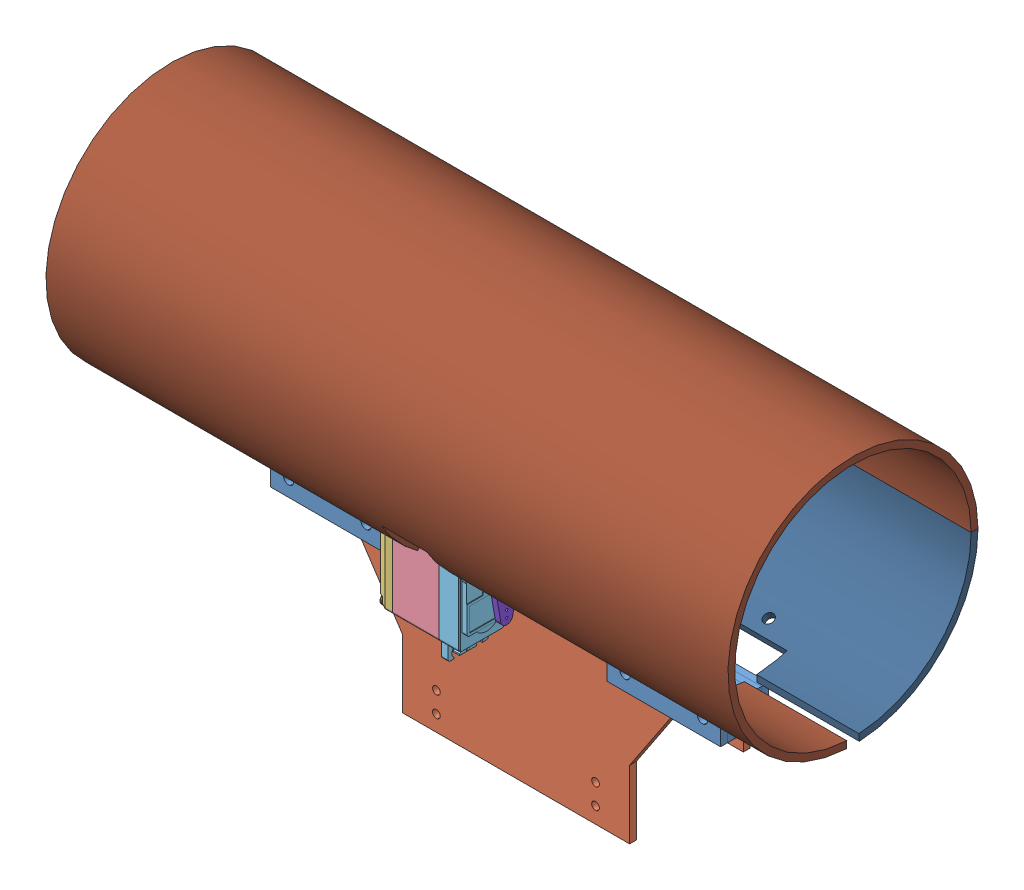
SolidWorks assembly CLAW, configuration Default. Lengths in mm.
Overall size (300 197.14 110).
37 component instances, 11 part files, 0 mates.
Components (placement in the parent):
- adjustmentHingePlate-1: adjustmentHingePlate [Default] at (-171.6086 67.3514 -20.0242) size (50 14 3)
- adjustmentHingePlate-2: adjustmentHingePlate [Default] at (-171.6086 67.3514 -23.0242) size (50 14 3)
- adjustmentHingePlate-3: adjustmentHingePlate [Default] at (-319.6086 67.3514 -17.0242) size (50 14 3)
- adjustmentHingePlate-4: adjustmentHingePlate [Default] at (-319.6086 67.3514 -20.0242) size (50 14 3)
- adjustmentHingePlate-5: adjustmentHingePlate [Default] at (-319.6086 67.3514 -23.0242) size (50 14 3)
- adjustmentHingePlate-6: adjustmentHingePlate [Default] at (-171.6086 67.3514 -5.0242) size (50 14 3)
- adjustmentHingePlate-7: adjustmentHingePlate [Default] at (-171.6086 67.3514 -8.0242) size (50 14 3)
- adjustmentHingePlate-8: adjustmentHingePlate [Default] at (-171.6086 67.3514 -11.0242) size (50 14 3)
- adjustmentHingePlate-9: adjustmentHingePlate [Default] at (-319.6086 67.3514 -5.0242) size (50 14 3)
- adjustmentHingePlate-10: adjustmentHingePlate [Default] at (-319.6086 67.3514 -8.0242) size (50 14 3)
- adjustmentHingePlate-11: adjustmentHingePlate [Default] at (-171.6086 67.3514 -17.0242) size (50 14 3)
- adjustmentHingePlate-12: adjustmentHingePlate [Default] at (-319.6086 67.3514 -11.0242) size (50 14 3)
- plate-1: plate [Default] at (-270.6086 1.3514 -14.0242) size (200 80 3)
- TOWER PRO MG-995, ANALOG SERVO-1: TOWER PRO MG-995, ANALOG SERVO [Default] at (-255.0724 76.6649 -23.9242) x (0 0 -1) z (0 -1 0) size (19.81 47.29 67)
  - TOWER PRO MG-995, ANALOG SERVO, BODY, BOTTOM-1: TOWER PRO MG-995, ANALOG SERVO, BODY, BOTTOM [Default] at origin size (19.81 6.4 40.61)
  - TOWER PRO MG-995, ANALOG SERVO, BODY, MIDDLE-1: TOWER PRO MG-995, ANALOG SERVO, BODY, MIDDLE [Default] at (0 10.25 0) size (19.8 20.5 40.6)
  - TOWER PRO MG-995, ANALOG SERVO, BODY, TOP-1: TOWER PRO MG-995, ANALOG SERVO, BODY, TOP [Default] at (0 20.5 0) size (19.8 13.2 54.6)
  - TOWER PRO MG-995, ANALOG SERVO, CONNECTOR-1: TOWER PRO MG-995, ANALOG SERVO, CONNECTOR [Default] at (0 -1.3147 -20.3) size (6.8 4.1 19.4)
  - TOWER PRO MG-995, ANALOG SERVO, SHAFT-1: TOWER PRO MG-995, ANALOG SERVO, SHAFT [Default] at (0 20.5 -10.3) x (-0.999988 0 -0.004881) z (0.004881 0 -0.999988) size (5.76 17.5 5.8)
  - TOWER PRO MG-995, ANALOG SERVO, HORN-1: TOWER PRO MG-995, ANALOG SERVO, HORN [Default] at (0 35 -10.3) x (0.999988 0 0.004881) z (-0.004881 0 0.999988) size (12.7 5.75 38.36)
  - pan cross head_am_B18.6.7M - M2 x 0.4 x 10 Type I Cross Recessed PHMS_ --10N-1: pan cross head_am_B18.6.7M - M2 x 0.4 x 10 Type I Cross Recessed PHMS_ --10N [Default] at (-7.7 -6.5 18.1) x (0 1 0) z (0 0 1) size (11.64 4 4.03)
  - pan cross head_am_B18.6.7M - M2 x 0.4 x 10 Type I Cross Recessed PHMS_ --10N-2: pan cross head_am_B18.6.7M - M2 x 0.4 x 10 Type I Cross Recessed PHMS_ --10N [Default] at (7.7 -6.5 18.1) x (0 1 0) z (0 0 1) size (11.64 4 4.03)
  - pan cross head_am_B18.6.7M - M2 x 0.4 x 10 Type I Cross Recessed PHMS_ --10N-3: pan cross head_am_B18.6.7M - M2 x 0.4 x 10 Type I Cross Recessed PHMS_ --10N [Default] at (7.7 -6.5 -18.1) x (0 1 0) z (0 0 1) size (11.64 4 4.03)
  - pan cross head_am_B18.6.7M - M2 x 0.4 x 10 Type I Cross Recessed PHMS_ --10N-4: pan cross head_am_B18.6.7M - M2 x 0.4 x 10 Type I Cross Recessed PHMS_ --10N [Default] at (-7.7 -6.5 -18.1) x (0 1 0) z (0 0 1) size (11.64 4 4.03)
- TOWER PRO MG-995, ANALOG SERVO-2: TOWER PRO MG-995, ANALOG SERVO [Default] at (-255.0724 76.6649 -1.1242) x (0 0 -1) z (0 -1 0) size (19.81 47.29 67)
  - TOWER PRO MG-995, ANALOG SERVO, BODY, BOTTOM-1: TOWER PRO MG-995, ANALOG SERVO, BODY, BOTTOM [Default] at origin size (19.81 6.4 40.61)
  - TOWER PRO MG-995, ANALOG SERVO, BODY, MIDDLE-1: TOWER PRO MG-995, ANALOG SERVO, BODY, MIDDLE [Default] at (0 10.25 0) size (19.8 20.5 40.6)
  - TOWER PRO MG-995, ANALOG SERVO, BODY, TOP-1: TOWER PRO MG-995, ANALOG SERVO, BODY, TOP [Default] at (0 20.5 0) size (19.8 13.2 54.6)
  - TOWER PRO MG-995, ANALOG SERVO, CONNECTOR-1: TOWER PRO MG-995, ANALOG SERVO, CONNECTOR [Default] at (0 -1.3147 -20.3) size (6.8 4.1 19.4)
  - TOWER PRO MG-995, ANALOG SERVO, SHAFT-1: TOWER PRO MG-995, ANALOG SERVO, SHAFT [Default] at (0 20.5 -10.3) x (-0.999988 0 -0.004881) z (0.004881 0 -0.999988) size (5.76 17.5 5.8)
  - TOWER PRO MG-995, ANALOG SERVO, HORN-1: TOWER PRO MG-995, ANALOG SERVO, HORN [Default] at (0 35 -10.3) x (0.999988 0 0.004881) z (-0.004881 0 0.999988) size (12.7 5.75 38.36)
  - pan cross head_am_B18.6.7M - M2 x 0.4 x 10 Type I Cross Recessed PHMS_ --10N-1: pan cross head_am_B18.6.7M - M2 x 0.4 x 10 Type I Cross Recessed PHMS_ --10N [Default] at (-7.7 -6.5 18.1) x (0 1 0) z (0 0 1) size (11.64 4 4.03)
  - pan cross head_am_B18.6.7M - M2 x 0.4 x 10 Type I Cross Recessed PHMS_ --10N-2: pan cross head_am_B18.6.7M - M2 x 0.4 x 10 Type I Cross Recessed PHMS_ --10N [Default] at (7.7 -6.5 18.1) x (0 1 0) z (0 0 1) size (11.64 4 4.03)
  - pan cross head_am_B18.6.7M - M2 x 0.4 x 10 Type I Cross Recessed PHMS_ --10N-3: pan cross head_am_B18.6.7M - M2 x 0.4 x 10 Type I Cross Recessed PHMS_ --10N [Default] at (7.7 -6.5 -18.1) x (0 1 0) z (0 0 1) size (11.64 4 4.03)
  - pan cross head_am_B18.6.7M - M2 x 0.4 x 10 Type I Cross Recessed PHMS_ --10N-4: pan cross head_am_B18.6.7M - M2 x 0.4 x 10 Type I Cross Recessed PHMS_ --10N [Default] at (-7.7 -6.5 -18.1) x (0 1 0) z (0 0 1) size (11.64 4 4.03)
- lowerClaw-1: lowerClaw [Default] at (-371.9616 143.4939 -65.6122) x (0 1 0) z (1 0 0) size (54.93 52.35 300)
- upperClaw-1: upperClaw [Default] at (-371.9616 143.4939 -65.6122) x (0 1 0) z (1 0 0) size (109.92 110 300)
